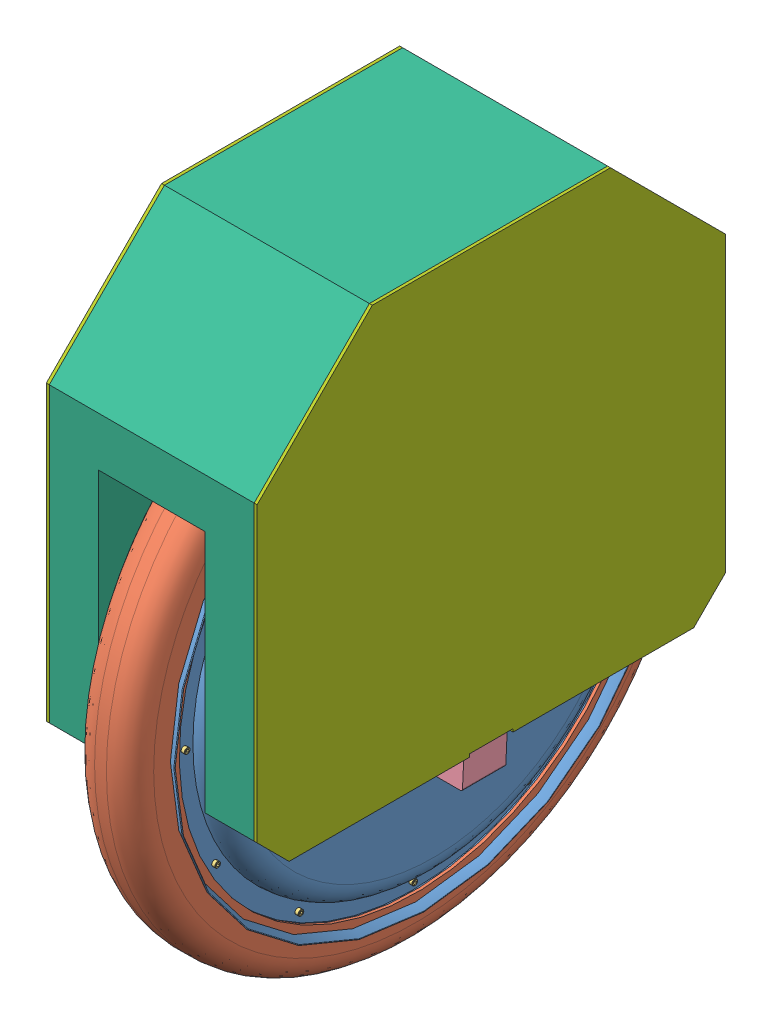
SolidWorks assembly euc0.3, configuration Default. Lengths in mm.
Overall size (364.75 810.04 810.04).
40 component instances, 14 part files, 34 mates.
Components (placement in the parent):
- wheel-1: wheel [Default] at origin size (217.51 810.04 810.04)
  - motor-1: motor [Default] at origin size (188.73 505.83 505.83)
  - tyre-1: tyre [Default] at (-29.8207 0 0) x (1 0 0) z (0 0.587098 0.809516) size (60 580 580)
  - socket head cap screw_ai-1: socket head cap screw_ai [HX-SHCS 0.138-40x0.188x0.188-N] at (29.5052 231 0) x (-1 0 0) z (0 0 -1) size (8.28 5.74 5.74)
  - socket head cap screw_ai-2: socket head cap screw_ai [HX-SHCS 0.138-40x0.188x0.188-N] at (29.5052 200.0519 -115.5) x (-1 0 0) z (0 -0.5 -0.866025) size (8.28 5.74 5.74)
  - socket head cap screw_ai-3: socket head cap screw_ai [HX-SHCS 0.138-40x0.188x0.188-N] at (29.5052 200.0519 115.5) x (-1 0 0) z (0 0.5 -0.866025) size (8.28 5.74 5.74)
  - socket head cap screw_ai-4: socket head cap screw_ai [HX-SHCS 0.138-40x0.188x0.188-N] at (29.5052 115.5 200.0519) x (-1 0 0) z (0 0.866025 -0.5) size (8.28 5.74 5.74)
  - socket head cap screw_ai-5: socket head cap screw_ai [HX-SHCS 0.138-40x0.188x0.188-N] at (29.5052 0 231) x (-1 0 0) z (0 1 0) size (8.28 5.74 5.74)
  - socket head cap screw_ai-6: socket head cap screw_ai [HX-SHCS 0.138-40x0.188x0.188-N] at (29.5052 -115.5 200.0519) x (-1 0 0) z (0 0.866025 0.5) size (8.28 5.74 5.74)
  - socket head cap screw_ai-7: socket head cap screw_ai [HX-SHCS 0.138-40x0.188x0.188-N] at (29.5052 -200.0519 115.5) x (-1 0 0) z (0 0.5 0.866025) size (8.28 5.74 5.74)
  - socket head cap screw_ai-8: socket head cap screw_ai [HX-SHCS 0.138-40x0.188x0.188-N] at (29.5052 -231 0) x (-1 0 0) z (0 0 1) size (8.28 5.74 5.74)
  - socket head cap screw_ai-9: socket head cap screw_ai [HX-SHCS 0.138-40x0.188x0.188-N] at (29.5052 -200.0519 -115.5) x (-1 0 0) z (0 -0.5 0.866025) size (8.28 5.74 5.74)
  - socket head cap screw_ai-10: socket head cap screw_ai [HX-SHCS 0.138-40x0.188x0.188-N] at (29.5052 -115.5 -200.0519) x (-1 0 0) z (0 -0.866025 0.5) size (8.28 5.74 5.74)
  - socket head cap screw_ai-11: socket head cap screw_ai [HX-SHCS 0.138-40x0.188x0.188-N] at (29.5052 0 -231) x (-1 0 0) z (0 -1 0) size (8.28 5.74 5.74)
  - socket head cap screw_ai-12: socket head cap screw_ai [HX-SHCS 0.138-40x0.188x0.188-N] at (29.5052 115.5 -200.0519) x (-1 0 0) z (0 -0.866025 -0.5) size (8.28 5.74 5.74)
  - socket head cap screw_ai-13: socket head cap screw_ai [HX-SHCS 0.138-40x0.188x0.188-N] at (-29.5052 231 0) size (8.28 5.74 5.74)
  - socket head cap screw_ai-14: socket head cap screw_ai [HX-SHCS 0.138-40x0.188x0.188-N] at (-29.5052 200.0519 -115.5) x (1 0 0) z (0 0.5 0.866025) size (8.28 5.74 5.74)
  - socket head cap screw_ai-15: socket head cap screw_ai [HX-SHCS 0.138-40x0.188x0.188-N] at (-29.5052 200.0519 115.5) x (1 0 0) z (0 -0.5 0.866025) size (8.28 5.74 5.74)
  - socket head cap screw_ai-16: socket head cap screw_ai [HX-SHCS 0.138-40x0.188x0.188-N] at (-29.5052 115.5 200.0519) x (1 0 0) z (0 -0.866025 0.5) size (8.28 5.74 5.74)
  - socket head cap screw_ai-17: socket head cap screw_ai [HX-SHCS 0.138-40x0.188x0.188-N] at (-29.5052 0 231) x (1 0 0) z (0 -1 0) size (8.28 5.74 5.74)
  - socket head cap screw_ai-18: socket head cap screw_ai [HX-SHCS 0.138-40x0.188x0.188-N] at (-29.5052 -115.5 200.0519) x (1 0 0) z (0 -0.866025 -0.5) size (8.28 5.74 5.74)
  - socket head cap screw_ai-19: socket head cap screw_ai [HX-SHCS 0.138-40x0.188x0.188-N] at (-29.5052 -200.0519 115.5) x (1 0 0) z (0 -0.5 -0.866025) size (8.28 5.74 5.74)
  - socket head cap screw_ai-20: socket head cap screw_ai [HX-SHCS 0.138-40x0.188x0.188-N] at (-29.5052 -231 0) x (1 0 0) z (0 0 -1) size (8.28 5.74 5.74)
  - socket head cap screw_ai-21: socket head cap screw_ai [HX-SHCS 0.138-40x0.188x0.188-N] at (-29.5052 -200.0519 -115.5) x (1 0 0) z (0 0.5 -0.866025) size (8.28 5.74 5.74)
  - socket head cap screw_ai-22: socket head cap screw_ai [HX-SHCS 0.138-40x0.188x0.188-N] at (-29.5052 -115.5 -200.0519) x (1 0 0) z (0 0.866025 -0.5) size (8.28 5.74 5.74)
  - socket head cap screw_ai-23: socket head cap screw_ai [HX-SHCS 0.138-40x0.188x0.188-N] at (-29.5052 0 -231) x (1 0 0) z (0 1 0) size (8.28 5.74 5.74)
  - socket head cap screw_ai-24: socket head cap screw_ai [HX-SHCS 0.138-40x0.188x0.188-N] at (-29.5052 115.5 -200.0519) x (1 0 0) z (0 0.866025 0.5) size (8.28 5.74 5.74)
  - pedal hanger1-1: pedal hanger1 [Default] at (128.9328 -140.4403 -75.0082) x (0.997537 -0.070149 0) z (-0.006861 -0.09757 0.995205) size (54.31 133.41 56.48)
  - pedal hanger2-1: pedal hanger2 [Default] at (-128.9328 -140.4403 75.0082) x (-0.997537 -0.070149 0) z (0.006861 -0.09757 -0.995205) size (54.31 133.41 56.48)
- mt60 fem-1: mt60 fem [Default] at (85.5155 -2.714 -4.2673) x (0 1 0) z (0.866025 0 -0.5) size (29 12 12.94) (hidden)
  - Мама^mt60 fem-1: Мама^mt60 fem [По умолчанию] at (18.214 0 0) x (0 0 -1) z (1 0 0) size (12.94 12 20) (virtual)
  - Колпачек 2^mt60 fem-1: Колпачек 2^mt60 fem [По умолчанию] at (35.714 0 0) x (0 0 -1) z (1 0 0) size (12.94 12 13) (virtual)
  - Деталь11^mt60 fem-1: Деталь11^mt60 fem [По умолчанию] at (44.714 0 0) x (0 0 -1) z (1 0 0) size (8 7.46 6.5) (virtual)
- Chassis^euc0.3-3: Chassis^euc0.3 [Default] at origin size (208 446.65 475.61) (virtual)
- Lid-1: Lid [Default] at (104 0 0) x (0 0 -1) z (1 0 0) size (475.61 446.65 3)
- Lid-2: Lid [Default] at (-104 0 0) x (0 0 1) z (-1 0 0) size (475.61 446.65 3)
- Battery-1: Battery [Default] at (75 -47.6654 124.2759) x (0 0 -1) z (1 0 0) size (162 240 36)
- Battery2-1: Battery2 [Default] at (75 -56.177 -111.8756) x (0 0 -1) z (1 0 0) size (162 260 36)
- Battery3-1: Battery3 [Default] at (-75 -53.3809 -117.2218) x (0 0 -1) z (1 0 0) size (162 260 36)
- Battery4-1: Battery4 [Default] at (-75 -49.6513 119.4462) x (0 0 -1) z (1 0 0) size (162 260 36)
Mates (geometry in assembly coordinates):
- Lock1: lock: unknown of wheel-1/pedal hanger1-1; unknown of Chassis-1/Internal chassis-1
- Parallel1: parallel anti-aligned: plane of Chassis-1/Internal chassis-1 through (0 28 0) normal (0 1 0); plane of mt60 fem-1/Copy of Мама^mt60 fem-1 through (90.0311 15.5 3.5538) normal (0 -1 0)
- Parallel2: parallel aligned: plane of Chassis-1/Internal chassis-1 through (57 28 288) normal (1 0 0); plane of mt60 fem-1/Copy of Мама^mt60 fem-1 through (93 29 3.5538) normal (1 0 0)
- Coincident3: coincident anti-aligned: plane of Chassis-1/Internal chassis-1 through (93 7.266 3.5) normal (-1 0 0); plane of mt60 fem-1/Copy of Мама^mt60 fem-1 through (93 29 3.5538) normal (1 0 0)
- Coincident4: coincident anti-aligned: plane of Chassis-1/Internal chassis-1 through (82.4378 7.266 2.5981) normal (0.5 0 -0.866025); plane of mt60 fem-1/Copy of Мама^mt60 fem-1 through (82.4845 29 2.625) normal (-0.5 0 0.866025)
- Coincident5: coincident aligned: plane of Chassis-1/Internal chassis-1 through (100 25 0) normal (0 -1 0); plane of mt60 fem-1/Copy of Мама^mt60 fem-1 through (83.9689 25 0.0538) normal (0 -1 0)
- Coincident18: coincident anti-aligned: plane of Chassis-1/Internal chassis-1 through (57 28 288) normal (1 0 0); plane of Battery1-1 through (57 187.8877 190.3024) normal (-1 0 0)
- Coincident23: coincident anti-aligned: plane of Chassis-1/Internal chassis-1 through (57 28 288) normal (1 0 0); plane of Battery2-2 through (57 212.7697 -24.9641) normal (-1 0 0)
- Parallel5: parallel aligned: plane of Chassis-1/Internal chassis-1 through (0 28 0) normal (0 1 0); plane of Battery1-1 through (75 187.8877 109.3024) normal (0 1 0)
- Parallel6: parallel aligned: plane of Chassis-1/Internal chassis-1 through (0 28 0) normal (0 1 0); plane of Battery2-2 through (75 212.7697 -105.9641) normal (0 1 0)
- InPlace2: in place: plane of ? through (57 28 288) normal (1 0 0); plane of ? through (57 0 0) normal (1 0 0); moOrthogonalPlaneRef_w of ? through (57 28 288) normal (1 0 0); plane of ? through (57 0 0) normal (0 1 0); plane of ? through (57 28 288) normal (1 0 0); plane of ? through (57 0 0) normal (0 0 -1); plane of ? through (57 28 288) normal (1 0 0); unknown of ?
- Coincident26: coincident aligned: plane of ?; plane of ?
- Coincident27: coincident aligned: moOrthogonalPlaneRef_w of Chassis-1/Internal chassis-1 through (57 0 0) normal (0 1 0); plane of Lid^euc0.2-2 through (57 0 0) normal (0 1 0)
- Coincident28: coincident anti-aligned: moOrthogonalPlaneRef_w of Chassis-1/Internal chassis-1 through (57 0 0) normal (0 0 1); plane of Lid^euc0.2-2 through (57 0 0) normal (0 0 -1)
- InPlace3: in place: plane of ? through (0 303.0294 0) normal (0 1 0); plane of ? through (0 303.0294 0) normal (0 1 0); plane of ? through (0 303.0294 0) normal (0 1 0); plane of ? through (0 303.0294 0) normal (0 0 -1); plane of ? through (0 303.0294 0) normal (0 1 0); plane of ? through (0 303.0294 0) normal (1 0 0); plane of ? through (0 303.0294 0) normal (0 1 0); unknown of ?
- Coincident1482: coincident aligned: plane of ?; plane of ?
- Coincident1483: coincident aligned: moOrthogonalPlaneRef_w of top chassis^euc0.2-1 through (0 303.0294 0) normal (0 0 -1); plane of Pcb plate^euc0.2-1 through (0 303.0294 0) normal (0 0 -1)
- Coincident1484: coincident anti-aligned: moOrthogonalPlaneRef_w of top chassis^euc0.2-1 through (0 303.0294 0) normal (-1 0 0); plane of Pcb plate^euc0.2-1 through (0 303.0294 0) normal (1 0 0)
- Coincident1488: coincident anti-aligned: plane of Pcb plate^euc0.2-1 through (-24 312.0294 76) normal (0 1 0); plane of pcb^euc0.2-1 through (0 312.0294 0) normal (0 -1 0)
- Coincident1489: coincident aligned: plane of Pcb plate^euc0.2-1 through (-40 307.0294 80) normal (0 0 1); plane of pcb^euc0.2-1 through (-28 315.0294 80) normal (0 0 1)
- Coincident1490: coincident anti-aligned: plane of Pcb plate^euc0.2-1 through (28 315.0294 -80) normal (-1 0 0); plane of pcb^euc0.2-1 through (28 315.0294 80) normal (1 0 0)
- Coincident1491: coincident anti-aligned: plane of Chassis-1/Internal chassis-1 through (57 28 288) normal (1 0 0); plane of Battery-2 through (57 183.6915 -26.6601) normal (-1 0 0)
- Coincident1492: coincident anti-aligned: plane of wheel-1/pedal hanger1-1 through (78 -21 22) normal (0.998924 -0.046379 0); plane of Chassis^euc0.3-1/Internal chassis^Chassis_euc0.3-1 through (78.6491 -7.0189 -11.33) normal (-0.998924 0.046379 0)
- InPlace4: in place: plane of ? through (104 0 237.8048) normal (1 0 0); plane of Lid-1 through (104 0 0) normal (1 0 0); plane of ? through (104 0 237.8048) normal (1 0 0); plane of Lid-1 through (104 0 0) normal (0 1 0); plane of ? through (104 0 237.8048) normal (1 0 0); plane of Lid-1 through (104 0 0) normal (0 0 -1); plane of ? through (104 0 237.8048) normal (1 0 0); unknown of Lid-1
- Coincident1493: coincident aligned: plane of ?; plane of ?
- Coincident1494: coincident aligned: moOrthogonalPlaneRef_w of Chassis^euc0.3-3 through (104 0 0) normal (0 1 0); plane of Lid^euc0.3-1 through (104 0 0) normal (0 1 0)
- Coincident1495: coincident anti-aligned: moOrthogonalPlaneRef_w of Chassis^euc0.3-3 through (104 0 0) normal (0 0 1); plane of Lid^euc0.3-1 through (104 0 0) normal (0 0 -1)
- Coincident1496: coincident anti-aligned: plane of Chassis^euc0.3-3 through (-104 0 237.8048) normal (-1 0 0); plane of Lid-2 through (-104 0 0) normal (1 0 0)
- Coincident1497: coincident aligned: plane of Chassis^euc0.3-3 through (-266.8954 375.6488 120.8782) normal (0 1 0); plane of Lid-2 through (-107 375.6488 120.8782) normal (0 1 0)
- Coincident1498: coincident aligned: plane of Chassis^euc0.3-3 through (0 0 237.8048) normal (0 0 1); plane of Lid-2 through (-107 -38.5515 237.8048) normal (0 0 1)
- Coincident1499: coincident anti-aligned: plane of Chassis^euc0.3-3 through (57 0 0) normal (1 0 0); plane of Battery-1 through (57 192.3346 205.2759) normal (-1 0 0)
- Coincident1500: coincident anti-aligned: plane of Chassis^euc0.3-3 through (57 0 0) normal (1 0 0); plane of Battery2-1 through (57 203.823 -30.8756) normal (-1 0 0)
- Coincident1501: coincident anti-aligned: plane of Chassis^euc0.3-3 through (-57 0 0) normal (-1 0 0); plane of Battery3-1 through (-57 206.6191 -36.2218) normal (1 0 0)
- Coincident1502: coincident anti-aligned: plane of Chassis^euc0.3-3 through (-57 0 0) normal (-1 0 0); plane of Battery4-1 through (-57 210.3487 200.4462) normal (1 0 0)
